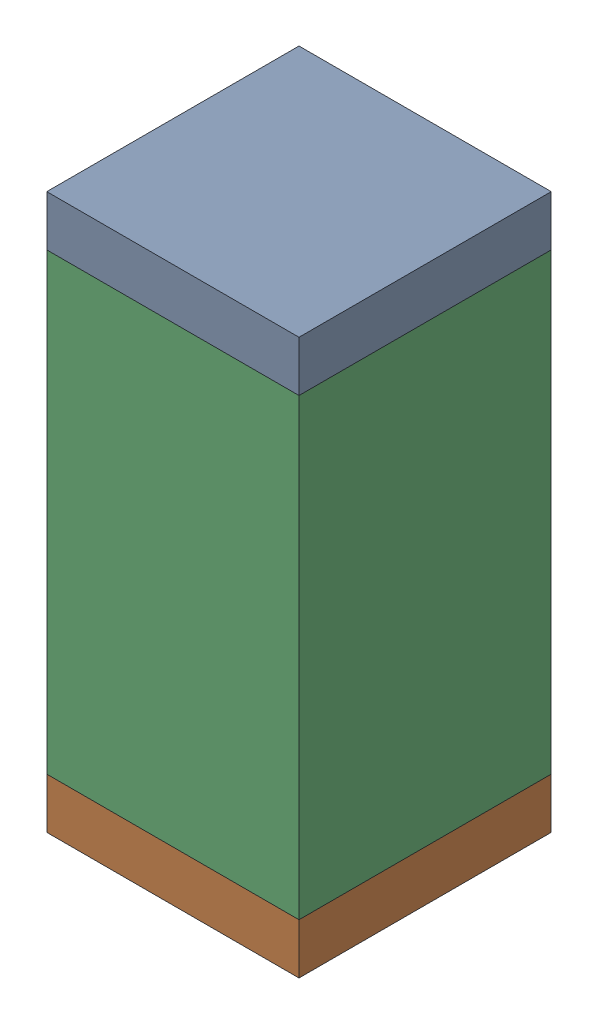
SolidWorks assembly R59, configuration Default. Lengths in mm.
Overall size (0.5 1.1 0.5).
6 component instances, 2 part files, 0 mates.
Components (placement in the parent):
- 810157360-1: 810157360 [Default] at (133.4 68.25 0) size (0.5 0.1 0.5)
  - Extruded_9-1: Extruded_9 [Default] at origin size (0.5 0.1 0.5)
- 810157360-2: 810157360 [Default] at (133.4 67.25 0) size (0.5 0.1 0.5)
  - Extruded_9-1: Extruded_9 [Default] at origin size (0.5 0.1 0.5)
- 791586336-1: 791586336 [Default] at (133.4 67.75 0) size (0.5 0.9 0.5)
  - Extruded_8-1: Extruded_8 [Default] at origin size (0.5 0.9 0.5)
